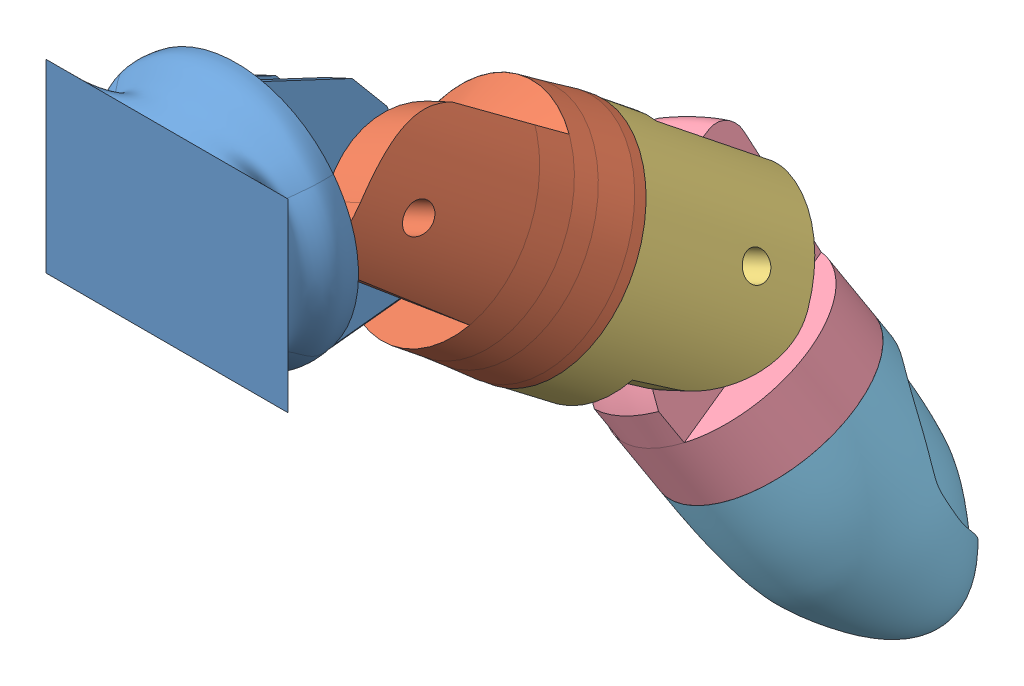
SolidWorks assembly deget mare, configuration Default. Lengths in mm.
Overall size (43.45 64.19 58.55).
5 component instances, 5 part files, 15 mates.
Components (placement in the parent):
- deget3-1: deget3 [Default] at origin size (24.28 22.96 17.51)
- deget 2-1: deget 2 [Default] at (5.185 -11.6868 -28.9168) x (-0.905973 -0.423336 0) z (-0.262459 0.561682 0.78462) size (20 20 23)
- deget-1: deget [Default] at (9.1429 -20.157 -40.7488) x (-0.262459 0.561682 0.78462) z (0.332158 -0.710844 0.619977) size (15.08 20.32 19.9)
- Thump50-1: Thump50 [Default] at (12.6343 -27.6289 -42.1434) x (-0.167923 0.359369 -0.917963) z (-0.388607 0.831649 0.396666) size (19.12 18.1 18.16)
- deget4-1: deget4 [Default] at (12.6343 -27.6289 -42.1434) x (0.905973 0.423336 0) z (-0.167923 0.359369 -0.917963) size (18 20.37 18.06)
Mates (geometry in assembly coordinates):
- Coincident2: coincident aligned: plane of deget3-1 through (0 0 0) normal (0 0 1)
- Coincident3: coincident aligned: plane of deget3-1 through (0 0 0) normal (0 1 0)
- Coincident4: coincident aligned: plane of deget3-1 through (0 0 0) normal (1 0 0)
- Concentric1: concentric aligned: cylinder of deget3-1 through (-4.4671 -6.3847 -13) axis (0.905973 0.423336 0) radius 1.25; cylinder of deget 2-1 through (-10.356 -9.1364 -13) axis (0.905973 0.423336 0) radius 1.25
- Coincident5: coincident anti-aligned: plane of deget3-1 through (4.7564 2.2225 -6) normal (0.905973 0.423336 0); plane of deget 2-1 through (12.1238 -13.5443 -13.7955) normal (-0.905973 -0.423336 0)
- LimitAngle1: limit planar angle = 2.361494 rad aligned: plane of deget3-1 through (0 0 0) normal (0 1 0); plane of deget 2-1 through (5.185 -11.6868 -28.9168) normal (0.332158 -0.710844 0.619977)
- Concentric2: concentric anti-aligned: cone of deget 2-1 through (4.9225 -11.1252 -28.1322) axis (-0.262459 0.561682 0.78462); cone of deget-1 through (4.4186 -10.0467 -26.6257) axis (0.262459 -0.561682 -0.78462)
- Coincident6: coincident anti-aligned: plane of deget 2-1 through (5.185 -11.6868 -28.9168) normal (0.262459 -0.561682 -0.78462); plane of deget-1 through (12.5208 1.787 -36.1084) normal (-0.262459 0.561682 0.78462)
- Coincident7: coincident aligned: plane of deget 2-1 through (5.185 -11.6868 -28.9168) normal (0.332158 -0.710844 0.619977); plane of deget-1 through (9.1429 -20.157 -40.7488) normal (0.332158 -0.710844 0.619977)
- Concentric3: concentric aligned: cylinder of deget-1 through (16.5581 -12.4044 -37.4457) axis (-0.905973 -0.423336 0) radius 1.25; cylinder of Thump50-1 through (12.0283 -14.5211 -37.4457) axis (-0.905973 -0.423336 0) radius 1.25
- Coincident8: coincident anti-aligned: plane of deget-1 through (12.0873 -18.7812 -40.7488) normal (-0.905973 -0.423336 0); plane of Thump50-1 through (8.0693 -10.1823 -42.829) normal (0.905973 0.423336 0)
- LimitAngle2: limit planar angle = 2.647392 rad aligned: plane of deget-1 through (9.1429 -20.157 -40.7488) normal (0.332158 -0.710844 0.619977); plane of Thump50-1 through (12.6343 -27.6289 -42.1434) normal (-0.167923 0.359369 -0.917963)
- Concentric5: concentric anti-aligned: cylinder of Thump50-1 through (10.4969 -23.0548 -39.9617) axis (0.388607 -0.831649 -0.396666) radius 9; circle of deget4-1
- Coincident12: coincident aligned: circle of Thump50-1; circle of deget4-1
- Coincident13: coincident anti-aligned: plane of Thump50-1 through (12.6343 -27.6289 -42.1434) normal (-0.905973 -0.423336 0); plane of deget4-1 through (12.6343 -27.6289 -42.1434) normal (0.905973 0.423336 0)
